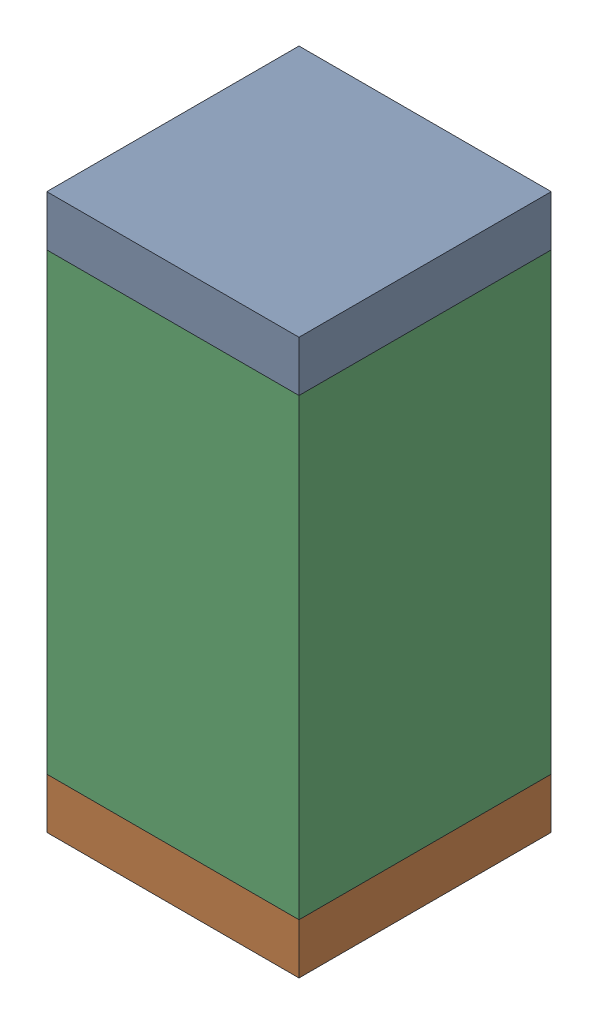
SolidWorks assembly C5, configuration Default. Lengths in mm.
Overall size (0.5 1.1 0.5).
6 component instances, 2 part files, 0 mates.
Components (placement in the parent):
- 810157360-1: 810157360 [Default] at (120.8 8.35 0) size (0.5 0.1 0.5)
  - Extruded_9-1: Extruded_9 [Default] at origin size (0.5 0.1 0.5)
- 810157360-2: 810157360 [Default] at (120.8 7.35 0) size (0.5 0.1 0.5)
  - Extruded_9-1: Extruded_9 [Default] at origin size (0.5 0.1 0.5)
- 791586336-1: 791586336 [Default] at (120.8 7.85 0) size (0.5 0.9 0.5)
  - Extruded_8-1: Extruded_8 [Default] at origin size (0.5 0.9 0.5)
